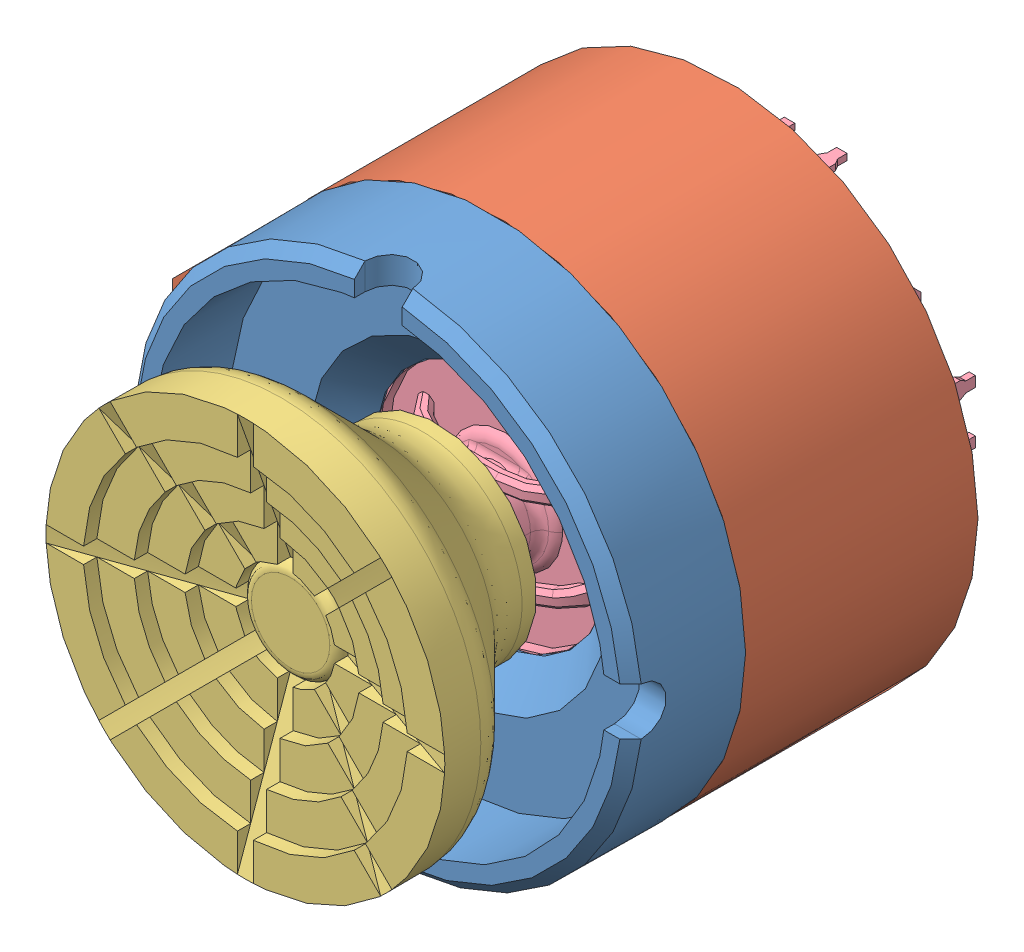
SolidWorks assembly TDC Switch, configuration Default. Lengths in mm.
Overall size (27.38 24.21 25.99).
4 component instances, 4 part files, 3 mates.
Components (placement in the parent):
- TDC Switch Body-1: TDC Switch Body [Default] at origin size (24.21 24.21 5.44)
- Lower TDC Switch Body-1: Lower TDC Switch Body [Default] at origin size (27.38 24.21 11.1)
- TDC Switch Cap-1: TDC Switch Cap [Default] at (0 0 4.699) size (19.05 19.05 9.14)
- RKJXV1224005-1: RKJXV1224005 [Default] at (0 0 -8.201) x (0 1 0) z (0 0 -1) size (21.27 17.79 21.85)
Mates (geometry in assembly coordinates):
- Concentric1: concentric anti-aligned: cylinder of TDC Switch Cap-1 through (0 0 9.271) axis (0 0 1) radius 9.525; cylinder of RKJXV1224005-1 through (0 0 -16.6056) axis (0 0 -1) radius 0.6
- Perpendicular1: perpendicular: plane of TDC Switch Cap-1 through (-0.381 9.5174 4.699) normal (1 0 0); plane of RKJXV1224005-1 through (-5.5 6.575 1.949) normal (0 1 0)
- Coincident1: coincident: plane of TDC Switch Cap-1 through (0 0 4.699) normal (0 0 -1); point of RKJXV1224005-1
